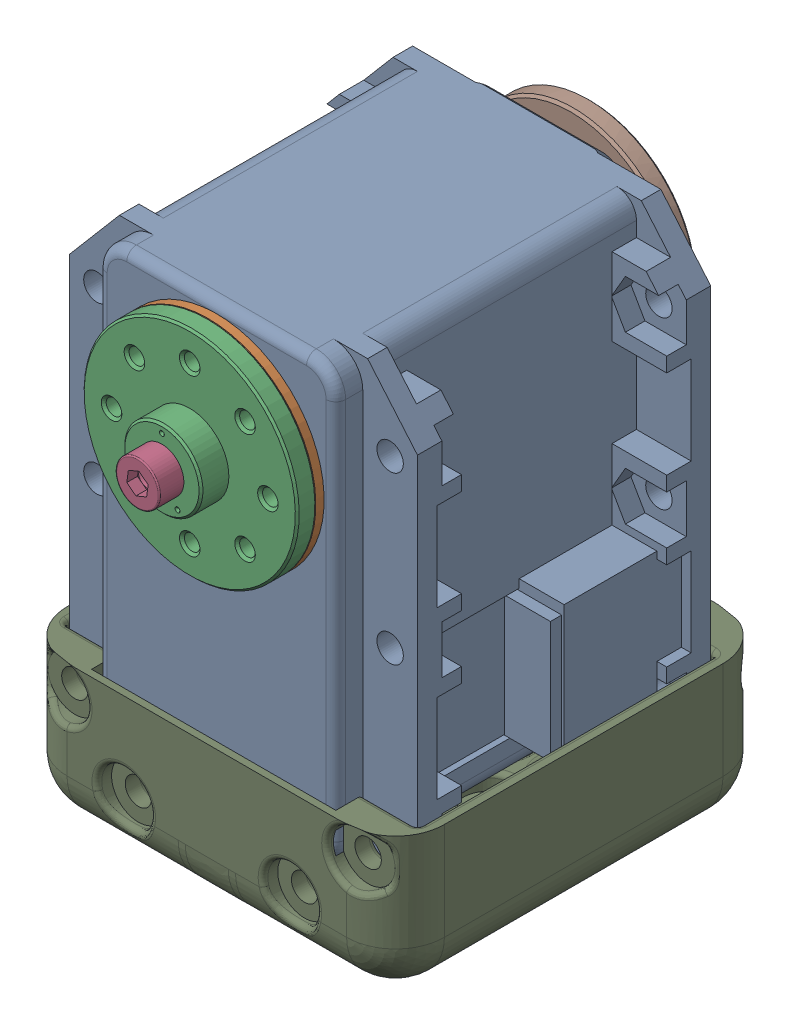
SolidWorks assembly shoulder_x, configuration Default. Lengths in mm.
Overall size (38.6 59.63 48.85).
10 component instances, 8 part files, 0 mates.
Components (placement in the parent):
- MX-28(U)-7-1: MX-28(U)-7 [Default] at (11.7145 14.4166 -1.625) size (35.6 54.13 48.5)
  - dynamixel_x28series(U)-1: dynamixel_x28series(U) [Default] at origin size (35.6 50.71 41.85)
  - trust_washer(U)-1: trust_washer(U) [Default] at (0 0 18.6) x (-0.666375 -0.745617 0) z (0.745617 -0.666375 0) size (22 0.85 22)
  - HN07-N101(U)-1: HN07-N101(U) [Default] at (0 0 18.5) x (1 0 0) z (0 -1 0) size (22 5.85 22)
  - WB_M2.5x8-1: WB_M2.5x8 [Default] at (0 0 25.85) x (0 0 -1) z (-0.991137 0.132843 0) size (10.5 4.5 4.5)
  - WB_M2.5x8-2: WB_M2.5x8 [Default] at (0 0 -22.65) x (0 0 1) z (-0.936501 0.350665 0) size (10.5 4.5 4.5)
  - RX28-CAP-1: RX28-CAP [Default] at (0 0 -20.35) x (-0.995735 -0.092256 0) z (0 0 -1) size (7.2 7.2 1.8)
  - MF106ZZ-1: MF106ZZ [Default] at (0 0 -20.35) x (0.888333 -0.4592 0) z (-0.4592 -0.888333 0) size (11.2 3 11.2)
  - HN07-i101-1: HN07-i101 [Default] at (0 0 -20.5) x (1 0 0) z (0 1 0) size (22 3.05 22)
- arm_connector-1: arm_connector [Default] at (11.7145 -28.1834 -11.625) size (38.6 17.77 41.99)
